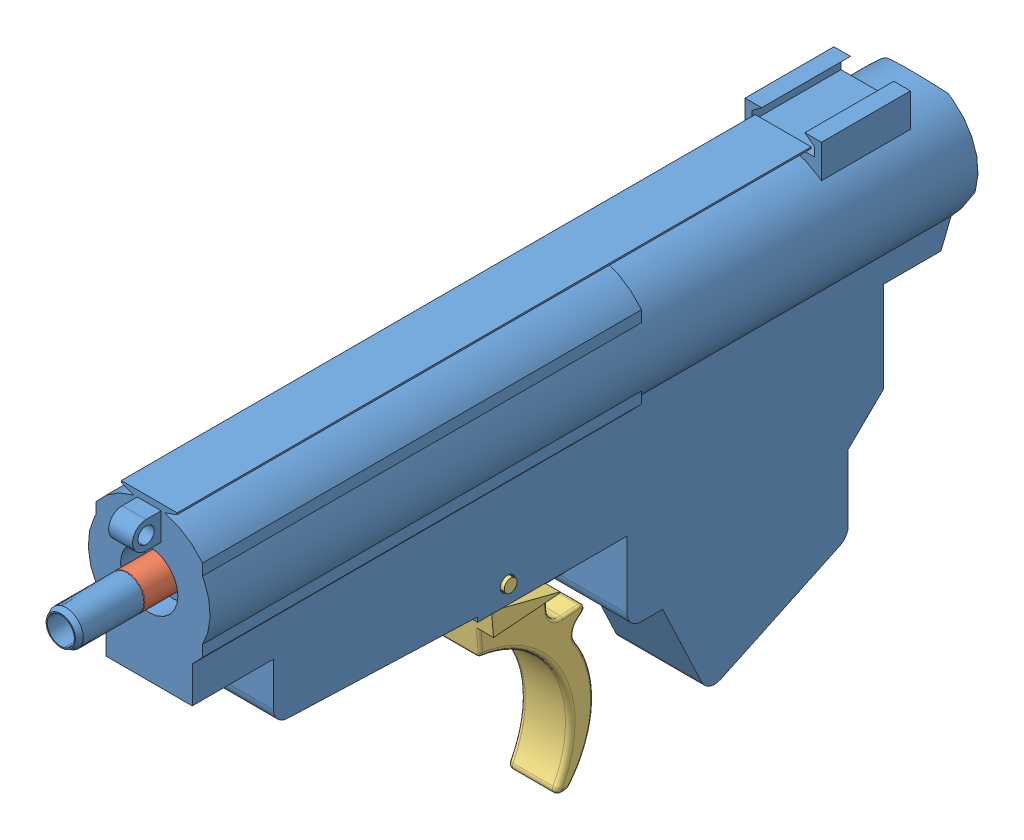
SolidWorks assembly NBB Box Nr1, configuration Standard. Lengths in mm.
Overall size (25.5 95.08 179.1).
6 component instances, 6 part files, 5 mates.
Components (placement in the parent):
- V3 GB mit allen wichtigen maßen-1: V3 GB mit allen wichtigen maßen [Standard] at (-8.9075 3.8216 0) size (25.5 86.02 179.1)
- G36 Nozzle-1: G36 Nozzle [Standard] at (3.8425 21.6759 50.3811) size (9 9 24.2)
- G36 Abzug-1: G36 Abzug [Standard] at (-2.9575 -4.7747 -50.8063) x (1 0 0) z (0 -0.078026 0.996951) size (19 51.7 22)
- NBB Gasrohr-1: NBB Gasrohr [Standard] at origin size (5.35 5.35 155)
- NBB Abzugstrebe-2: NBB Abzugstrebe [Standard] at (0.3 0.0046 0.0411) x (1 0 0) z (0 -0.005395 0.999985) size (10.5 47.97 13.15)
- NBB Gasrohrmantel für Nozzle-1: NBB Gasrohrmantel für Nozzle [Standard] at origin size (9 9 51)
Mates (geometry in assembly coordinates):
- Sperren3: lock: unknown of ?; unknown of ?
- Konzentrisch8: concentric anti-aligned: cylinder of V3 GB mit allen wichtigen maßen-1 through (-13.1575 -7.6241 0.8811) axis (1 0 0) radius 1.6; cylinder of G36 Abzug-1 through (13.4425 -7.6241 0.8811) axis (-1 0 0) radius 1.35
- Abstand2: distance = 0.6 mm aligned: plane of G36 Abzug-1 through (13.4425 -7.6241 0.8811) normal (1 0 0); plane of V3 GB mit allen wichtigen maßen-1 through (12.8425 -47.8241 -93.7189) normal (1 0 0)
- Konzentrisch9: concentric aligned: cylinder of G36 Nozzle-1 through (3.8425 21.6759 82.8569) axis (0 0 1) radius 2.675; cylinder of NBB Gasrohr-1 through (3.8425 21.6759 -88.1189) axis (0 0 1) radius 2.675
- Abstand3: distance = 14.5 mm aligned: plane of G36 Nozzle-1 through (3.8425 26.1759 52.3811) normal (0 0 1); plane of V3 GB mit allen wichtigen maßen-1 through (16.5925 36.6759 66.8811) normal (0 0 1)
